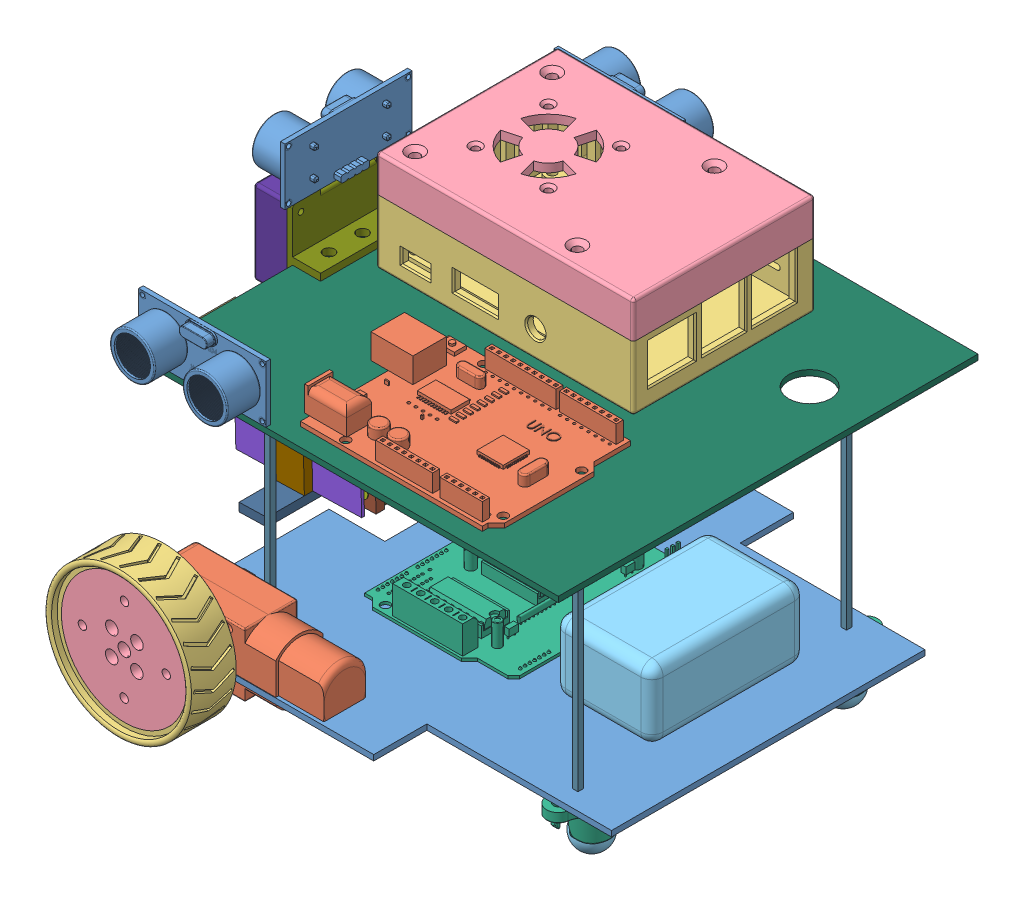
SolidWorks assembly Robo, configuration Default. Lengths in mm.
Overall size (198.95 162.78 193.09).
44 component instances, 24 part files, 52 mates.
Components (placement in the parent):
- Chassie-1: Chassie [Default] at (56.3992 70.6772 119.4071) size (150 2 150)
- wheel-1: wheel [Default] at (-59.9248 68.2072 35.5851) x (0 0 -1) z (0.96637 0.257157 0) size (47.16 66.76 87.56)
  - dc_motor_with_wheel-1: dc_motor_with_wheel [Défaut] at origin size (37.6 36.38 67.23)
  - tyre-1: tyre [Default] at (1.5267 -5.0802 53) x (1 0 0) z (0 0.34528 0.9385) size (16.83 52 52)
  - wheel_3wholes_outerlayer-1: wheel_3wholes_outerlayer [Default] at (7.5267 -5.0802 53) x (0 -0.603955 0.797018) z (0 -0.797018 -0.603955) size (45 4 45)
- wheel-2: wheel [Default] at (-59.9248 85.6472 203.229) x (0 0 1) z (0.96637 -0.257157 0) size (47.16 66.76 87.56)
  - dc_motor_with_wheel-1: dc_motor_with_wheel [Défaut] at origin size (37.6 36.38 67.23)
  - tyre-1: tyre [Default] at (1.5267 -5.0802 53) x (1 0 0) z (0 0.34528 0.9385) size (16.83 52 52)
  - wheel_3wholes_outerlayer-1: wheel_3wholes_outerlayer [Default] at (7.5267 -5.0802 53) x (0 -0.603955 0.797018) z (0 -0.797018 -0.603955) size (45 4 45)
- ball_v2-1: ball_v2 [Default] at (114.5561 64.9929 70.0782) x (-0.994727 0.101202 0.016649) z (0.102116 0.992387 0.068845) size (19.98 29.54 22.65)
  - ball-1: ball [Predeterminado] at (1.5642 3.9174 -7.4116) x (0.97009 -0.147809 -0.192554) z (0.182549 -0.078633 0.980047) size (12.6 12.6 12.6)
  - bas-1: bas [Predeterminado] at (3.6231 4.1003 3.995) x (-0.016649 -0.997488 -0.068845) z (0.994727 -0.009555 -0.102116) size (28.57 12.2 18.37)
- ball_v2-2: ball_v2 [Default] at (114.5561 64.9929 159.8852) x (-0.994727 0.101202 0.016649) z (0.102116 0.992387 0.068845) size (19.98 29.54 22.65)
  - ball-1: ball [Predeterminado] at (1.5642 3.9174 -7.4116) x (0.97009 -0.147809 -0.192554) z (0.182549 -0.078633 0.980047) size (12.6 12.6 12.6)
  - bas-1: bas [Predeterminado] at (3.6231 4.1003 3.995) x (-0.016649 -0.997488 -0.068845) z (0.994727 -0.009555 -0.102116) size (28.57 12.2 18.37)
- gripper-1: gripper [Default] at (95.6972 294.7422 312.9195) x (0.383049 0 0.923728) z (0 -1 0) size (92.65 69.09 65.38)
  - Servo-1: Servo [Default] at (-244.1629 10.2538 215.865) x (0.383049 -0.923728 0) z (0 0 1) size (27.6 29.9 12.4)
  - pad-1: pad [Default] at (-243.8055 16.9469 180.3776) x (-0.010204 0.024608 -0.999645) z (-0.923728 -0.383049 0) size (45 45 1)
  - pad-2: pad [Default] at (-199.6069 35.275 180.3776) x (-0.010204 0.024608 -0.999645) z (0.923728 0.383049 0) size (45 45 1)
  - arm-1: arm [Default] at (-244.7292 16.5638 180.3776) x (-0.010204 0.024608 -0.999645) z (-0.923728 -0.383049 0) size (45 10 3)
  - arm-3: arm [Default] at (-198.6831 35.6581 180.3776) x (-0.010204 0.024608 -0.999645) z (0.923728 0.383049 0) size (45 10 3)
  - Part12^gripper-1: Part12^gripper [Default] at (-220.2923 26.0484 202.8696) x (0.010204 -0.024608 0.999645) z (-0.923728 -0.383049 0) size (3 10 80) (virtual)
  - Part13^gripper-1: Part13^gripper [Default] at (-221.5708 25.2154 213.3659) x (0.923728 0.383049 0) z (0.010204 -0.024608 0.999645) size (3 10 15) (virtual)
  - Part14^gripper-1: Part14^gripper [Default] at (-256.1442 20.5956 158.0854) x (0.923728 0.383049 0) z (-0.382913 0.9234 0.02664) size (20 1 30) (virtual)
  - Part14^gripper-2: Part14^gripper [Default] at (-193.4812 46.6093 157.0858) x (-0.923728 -0.383049 0) z (-0.382913 0.9234 0.02664) size (20 1 30) (virtual)
- IR Sensor-1: IR Sensor [Default] at (11.3992 70.6772 119.4071) x (0 0 1) z (1 0 0) size (110 9 22)
- bar-1: bar [Default] at (2.3992 72.6772 168.4071) size (2 80 2)
- bar-2: bar [Default] at (0.3992 72.6772 70.4071) x (-1 0 0) z (0 0 -1) size (2 80 2)
- bar-4: bar [Default] at (112.3992 72.6772 168.4071) size (2 80 2)
- bar-6: bar [Default] at (110.3992 72.6772 70.4071) x (-1 0 0) z (0 0 -1) size (2 80 2)
- ChassieTop-1: ChassieTop [Default] at (56.3992 152.6772 119.4071) size (150 2 150)
- Cam hosuing Assembly-1: Cam hosuing Assembly [Default] at (-5.1029 127.1366 128.1973) x (0 0 -1) z (0 1 0) size (40 24 30)
  - Camera case bottomV3-1: Camera case bottomV3 [Default] at (8.7902 13.4979 31.0406) size (40 18 30)
  - Camera Case Top-1: Camera Case Top [Default] at (8.7902 25.4979 31.0406) x (1 0 0) z (0 1 0) size (40 30 12)
  - Raspberry Pi-1: Raspberry Pi [Default] at (8.7902 18.4979 31.7906) x (1 0 0) z (0 1 0) size (25 24 8)
- Sensor Ultrasonic-1: Sensor Ultrasonic [Predeterminado] at (4.1092 164.8472 194.4071) size (45.42 20.34 16)
- Sensor Ultrasonic-2: Sensor Ultrasonic [Predeterminado] at (4.1092 164.8472 44.4071) x (-1 0 0) z (0 0 -1) size (45.42 20.34 16)
- Sensor Ultrasonic-3: Sensor Ultrasonic [Predeterminado] at (-20.2008 183.3472 119.4071) x (0 0 1) z (-1 0 0) size (45.42 20.34 16)
- arduino_UNO-1: arduino_UNO [Default] at (32.7088 154.6772 134.9119) size (74.2 10.6 53)
- new assembly-1: new assembly [Default] at (7.8571 132.3466 37.7465) size (92 36 65)
  - enclosure bottom-1: enclosure bottom [Default] at (35.2616 22.3306 87.5788) size (92 28 65)
  - enclosure top-1: enclosure top [Default] at (35.2616 55.3306 55.0788) size (92 13 65)
- battery-1: battery [Default] at (55.734 72.6772 119.8314) x (-1 0 0) z (0 0 -1) size (52.22 25 123.6)
- Part1-1: Part1 [Default] at (41.4025 72.6772 115.5042) x (0 0 1) z (0 1 0) size (68.8 53.3 11.5)
Mates (geometry in assembly coordinates):
- Coincident1: coincident aligned: plane of Chassie-1 through (-18.6008 72.6772 44.4071) normal (-1 0 0); plane of wheel-1/dc_motor_with_wheel-1 through (-18.6008 65.6772 44.6071) normal (-1 0 0)
- Coincident3: coincident: plane of Chassie-1 through (-18.6008 70.6762 63.4071) normal (0 0 -1); plane of wheel-1/dc_motor_with_wheel-1 through (-7.4008 76.9272 63.4071) normal (0 0 1)
- Distance1: distance = 5 mm aligned: plane of Chassie-1 through (56.3992 70.6772 119.4071) normal (0 -1 0); plane of wheel-1/dc_motor_with_wheel-1 through (19.1992 65.6772 44.6071) normal (0 -1 0)
- Coincident5: coincident aligned: plane of Chassie-1 through (-18.6008 72.6772 44.4071) normal (-1 0 0); plane of wheel-2/dc_motor_with_wheel-1 through (-18.6008 88.1772 194.2071) normal (-1 0 0)
- Coincident6: coincident: plane of Chassie-1 through (-18.6008 70.6762 175.4071) normal (0 0 1); plane of wheel-2/dc_motor_with_wheel-1 through (-7.4008 76.9272 175.4071) normal (0 0 -1)
- Distance2: distance = 5 mm aligned: plane of wheel-2/dc_motor_with_wheel-1 through (-18.6008 65.6772 194.2071) normal (0 -1 0); plane of Chassie-1 through (56.3992 70.6772 119.4071) normal (0 -1 0)
- Coincident53: coincident anti-aligned: plane of Chassie-1 through (56.3992 70.6772 119.4071) normal (0 -1 0); plane of ball_v2-1/bas-1 through (117.1358 70.6772 85.4515) normal (0 1 0)
- Coincident55: coincident: line of Chassie-1 through (111.3992 70.6772 194.4071) axis (0 0 -1)
- Coincident56: coincident: line of Chassie-1 through (111.3992 70.6772 194.4071) axis (0 0 -1)
- Distance12: distance = 20 mm: line of assembly; point of ball_v2-1/bas-1; line of Chassie-1 through (65.3992 70.6772 44.4071) axis (-1 0 0)
- Coincident58: coincident anti-aligned: plane of Chassie-1 through (56.3992 70.6772 119.4071) normal (0 -1 0); plane of ball_v2-2/bas-1 through (117.1358 70.6772 175.2585) normal (0 1 0)
- Coincident59: coincident: line of Chassie-1 through (111.3992 70.6772 194.4071) axis (0 0 -1)
- Coincident62: coincident: line of Chassie-1 through (111.3992 70.6772 194.4071) axis (0 0 -1)
- Distance13: distance = 20 mm: line of assembly; point of ball_v2-2/bas-1; line of Chassie-1 through (-18.6008 70.6772 194.4071) axis (1 0 0)
- Coincident67: coincident anti-aligned: plane of Chassie-1 through (56.3992 72.6772 119.4071) normal (0 1 0); plane of gripper-1/Servo-1 through (-18.6008 72.6772 113.6071) normal (0 -1 0)
- Coincident68: coincident aligned: plane of Chassie-1 through (-18.6008 72.6772 44.4071) normal (-1 0 0); plane of gripper-1/Servo-1 through (-18.6008 72.6772 113.6071) normal (-1 0 0)
- Distance14: distance = 54.5 mm anti-aligned: plane of wheel-2/dc_motor_with_wheel-1 through (-7.4008 76.9272 175.4071) normal (0 0 -1); plane of gripper-1/Part13^gripper-1 through (-12.4674 81.3763 120.9071) normal (0 0 1)
- Coincident70: coincident anti-aligned: plane of Chassie-1 through (56.3992 70.6772 119.4071) normal (0 -1 0); plane of IR Sensor-1 through (11.3992 70.6772 119.4071) normal (0 1 0)
- Coincident71: coincident aligned: plane of Chassie-1 through (1.3992 70.6762 111.4071) normal (-1 0 0); plane of IR Sensor-1 through (1.3992 68.6772 174.4071) normal (-1 0 0)
- Distance15: distance = 1 mm anti-aligned: plane of wheel-2/dc_motor_with_wheel-1 through (-7.4008 76.9272 175.4071) normal (0 0 -1); plane of IR Sensor-1 through (21.3992 68.6772 174.4071) normal (0 0 1)
- Coincident73: coincident anti-aligned: plane of Chassie-1 through (56.3992 72.6772 119.4071) normal (0 1 0); plane of bar-1 through (2.3992 72.6772 168.4071) normal (0 -1 0)
- Parallel5: parallel aligned: plane of Chassie-1 through (-18.6008 72.6772 194.4071) normal (0 0 1); plane of bar-1 through (1.3992 152.6772 169.4071) normal (0 0 1)
- Coincident75: coincident: line of assembly; point of Chassie-1; line of bar-1 through (1.3992 152.6772 169.4071) axis (0 -1 0)
- Coincident76: coincident anti-aligned: plane of Chassie-1 through (56.3992 72.6772 119.4071) normal (0 1 0); plane of bar-2 through (0.3992 72.6772 70.4071) normal (0 -1 0)
- Parallel6: parallel aligned: plane of Chassie-1 through (-18.6008 72.6772 44.4071) normal (0 0 -1); plane of bar-2 through (1.3992 152.6772 69.4071) normal (0 0 -1)
- Coincident77: coincident: line of assembly; point of Chassie-1; line of bar-2 through (1.3992 152.6772 69.4071) axis (0 -1 0)
- Coincident78: coincident anti-aligned: plane of Chassie-1 through (56.3992 72.6772 119.4071) normal (0 1 0); plane of bar-4 through (112.3992 72.6772 168.4071) normal (0 -1 0)
- Parallel7: parallel aligned: plane of Chassie-1 through (-18.6008 72.6772 194.4071) normal (0 0 1); plane of bar-4 through (111.3992 152.6772 169.4071) normal (0 0 1)
- Coincident79: coincident: line of assembly; point of Chassie-1; line of bar-4 through (111.3992 152.6772 169.4071) axis (0 -1 0)
- Coincident80: coincident anti-aligned: plane of Chassie-1 through (56.3992 72.6772 119.4071) normal (0 1 0); plane of bar-6 through (110.3992 72.6772 70.4071) normal (0 -1 0)
- Parallel8: parallel aligned: plane of Chassie-1 through (-18.6008 72.6772 44.4071) normal (0 0 -1); plane of bar-6 through (111.3992 152.6772 69.4071) normal (0 0 -1)
- Coincident81: coincident: line of assembly; point of Chassie-1; line of bar-6 through (111.3992 152.6772 69.4071) axis (0 -1 0)
- Coincident87: coincident anti-aligned: plane of bar-1 through (2.3992 152.6772 168.4071) normal (0 1 0); plane of ChassieTop-1 through (56.3992 152.6772 119.4071) normal (0 -1 0)
- Coincident88: coincident aligned: plane of Chassie-1 through (-18.6008 72.6772 194.4071) normal (0 0 1); plane of ChassieTop-1 through (-18.6008 154.6772 194.4071) normal (0 0 1)
- Coincident89: coincident aligned: plane of Chassie-1 through (-18.6008 72.6772 44.4071) normal (-1 0 0); plane of ChassieTop-1 through (-18.6008 154.6772 44.4071) normal (-1 0 0)
- Coincident90: coincident anti-aligned: plane of ChassieTop-1 through (56.3992 154.6772 119.4071) normal (0 1 0); plane of Cam hosuing Assembly-1/Camera case bottomV3-1 through (-8.6008 154.6772 139.4071) normal (0 -1 0)
- Coincident91: coincident anti-aligned: plane of ChassieTop-1 through (-18.6008 154.6772 44.4071) normal (-1 0 0); plane of Cam hosuing Assembly-1/Camera case bottomV3-1 through (-18.6008 158.1772 119.4071) normal (1 0 0)
- Distance16: distance = 55 mm aligned: plane of ChassieTop-1 through (-18.6008 154.6772 194.4071) normal (0 0 1); plane of Cam hosuing Assembly-1/Camera case bottomV3-1 through (-20.6008 143.1772 139.4071) normal (0 0 1)
- Coincident93: coincident anti-aligned: plane of ChassieTop-1 through (56.3992 154.6772 119.4071) normal (0 1 0); plane of Sensor Ultrasonic-1 through (-18.6008 154.6772 192.8071) normal (0 -1 0)
- Coincident94: coincident aligned: plane of ChassieTop-1 through (-18.6008 154.6772 194.4071) normal (0 0 1); plane of Sensor Ultrasonic-1 through (4.1092 164.8472 194.4071) normal (0 0 1)
- Coincident95: coincident aligned: plane of ChassieTop-1 through (-18.6008 154.6772 44.4071) normal (-1 0 0); plane of Sensor Ultrasonic-1 through (-18.6008 154.6772 192.8071) normal (-1 0 0)
- Coincident96: coincident anti-aligned: plane of ChassieTop-1 through (56.3992 154.6772 119.4071) normal (0 1 0); plane of Sensor Ultrasonic-2 through (26.8192 154.6772 46.0071) normal (0 -1 0)
- Coincident97: coincident aligned: plane of ChassieTop-1 through (-18.6008 154.6772 44.4071) normal (0 0 -1); plane of Sensor Ultrasonic-2 through (4.1092 164.8472 44.4071) normal (0 0 -1)
- Coincident98: coincident aligned: plane of ChassieTop-1 through (-18.6008 154.6772 44.4071) normal (-1 0 0); plane of Sensor Ultrasonic-2 through (-18.6008 154.6772 46.0071) normal (-1 0 0)
- Coincident102: coincident anti-aligned: plane of Cam hosuing Assembly-1/Camera case bottomV3-1 through (-20.6008 173.1772 139.4071) normal (0 1 0); plane of Sensor Ultrasonic-3 through (-18.6008 173.1772 96.6971) normal (0 -1 0)
- Coincident103: coincident aligned: plane of Cam hosuing Assembly-1/Camera case bottomV3-1 through (-18.6008 158.1772 119.4071) normal (1 0 0); plane of Sensor Ultrasonic-3 through (-18.6008 183.3472 119.4071) normal (1 0 0)
- Distance17: distance = 52.29 mm aligned: plane of Sensor Ultrasonic-3 through (-18.6008 173.1772 142.1171) normal (0 0 1); plane of ChassieTop-1 through (-18.6008 154.6772 194.4071) normal (0 0 1)
- Coincident111: coincident anti-aligned: plane of ChassieTop-1 through (56.3992 154.6772 119.4071) normal (0 1 0); plane of new assembly-1/enclosure bottom-1 through (43.1186 154.6772 125.3253) normal (0 -1 0)
- Coincident113: coincident anti-aligned: plane of Chassie-1 through (56.3992 72.6772 119.4071) normal (0 1 0); plane of battery-1 through (55.734 72.6772 119.8314) normal (0 -1 0)
- Coincident116: coincident anti-aligned: plane of Chassie-1 through (56.3992 72.6772 119.4071) normal (0 1 0); plane of Part1-1 through (41.4025 72.6772 115.5042) normal (0 -1 0)
- Coincident119: coincident anti-aligned: plane of ChassieTop-1 through (56.3992 154.6772 119.4071) normal (0 1 0); plane of arduino_UNO-1 through (32.7088 154.6772 134.9119) normal (0 -1 0)
- Parallel15: parallel anti-aligned: plane of Chassie-1 through (-18.6008 72.6772 44.4071) normal (0 0 -1); plane of battery-1 through (114.144 97.6772 143.6794) normal (0 0 1)
